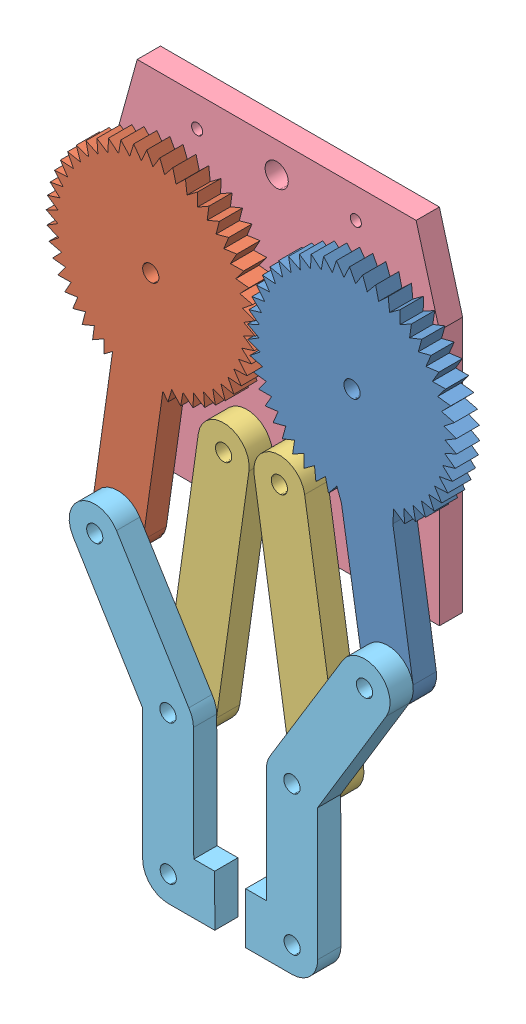
SolidWorks assembly XX, configuration Default. Lengths in mm.
Overall size (106.15 143.99 15).
7 component instances, 5 part files, 14 mates.
Components (placement in the parent):
- p1-1: p1 [Default] at (-416.0921 -344.6097 60.3759) x (0.988737 0.149664 0) z (0 0 1) size (44.91 78 5)
- p1_2-1: p1_2 [Default] at (-541.6496 -222.5672 60.3759) x (0.982822 -0.184555 0) z (0 0 1) size (44.97 77.99 5)
- p2-1: p2 [Default] at (-536.8195 -350.683 60.3759) x (0.990197 -0.139681 0) z (0 0 1) size (11 61 5)
- p2-2: p2 [Default] at (-401.013 -461.8626 60.3759) x (0.988113 0.153729 0) z (0 0 1) size (11 61 5)
- p4-1: p4 [Default] at (-493.5374 -239.3205 55.3759) x (1 0.000279 0) z (0 0 1) size (70 73.03 5)
- p33-2: p33 [Default] at (-38.5492 -79.1672 65.3759) x (0.999998 0.001877 0) z (0 0 1) size (31.17 66.58 5)
- p33-3: p33 [Default] at (-148.7564 -79.4572 70.3759) x (-0.999997 -0.002492 0) z (0 0 -1) size (31.17 66.58 5)
Mates (geometry in assembly coordinates):
- Coincident57: coincident anti-aligned: plane of p1_2-1 through (-541.6496 -222.5672 60.3759) normal (0 0 -1); plane of p4-1 through (-493.5374 -239.3205 60.3759) normal (0 0 1)
- Coincident60: coincident anti-aligned: plane of p2-1 through (-107.0776 -38.4044 60.3759) normal (0 0 -1); plane of p4-1 through (-493.5374 -239.3205 60.3759) normal (0 0 1)
- Coincident61: coincident anti-aligned: plane of p1-1 through (-64.7801 -12.6883 60.3759) normal (0 0 -1); plane of p4-1 through (-493.5374 -239.3205 60.3759) normal (0 0 1)
- Concentric44: concentric aligned: circle of p1-1; circle of p4-1
- Concentric45: concentric aligned: circle of p1_2-1; circle of p4-1
- GearMate1: gear = 3.5 : 3.5 mm: circle of p1_2-1; circle of p1-1
- Concentric66: concentric anti-aligned: cylinder of p1_2-1 through (-122.8162 -12.8644 65.3759) axis (0 0 -1) radius 1.75; cylinder of p33-3 through (-122.8162 -12.8644 65.3759) axis (0 0 1) radius 1.75
- Concentric67: concentric anti-aligned: cylinder of p2-1 through (-107.0776 -38.4044 65.3759) axis (0 0 -1) radius 1.75; cylinder of p33-3 through (-107.0776 -38.4044 65.3759) axis (0 0 1) radius 1.75
- Concentric68: concentric aligned: cylinder of p2-2 through (-80.407 -38.2969 65.3759) axis (0 0 -1) radius 1.75; cylinder of p33-2 through (-80.407 -38.2969 70.3759) axis (0 0 -1) radius 1.75
- Concentric69: concentric aligned: cylinder of p1-1 through (-64.7801 -12.6883 65.3759) axis (0 0 -1) radius 1.75; cylinder of p33-2 through (-64.7801 -12.6883 70.3759) axis (0 0 -1) radius 1.75
- Coincident74: coincident anti-aligned: plane of p2-1 through (-107.0776 -38.4044 65.3759) normal (0 0 1); plane of p33-3 through (-122.8162 -12.8644 65.3759) normal (0 0 -1)
- Coincident75: coincident anti-aligned: plane of p2-2 through (-80.407 -38.2969 65.3759) normal (0 0 1); plane of p33-2 through (-64.7801 -12.6883 65.3759) normal (0 0 -1)
- Concentric70: concentric aligned: cylinder of p2-1 through (-100.0935 11.1054 65.3759) axis (0 0 -1) radius 1.75; cylinder of p4-1 through (-100.0935 11.1054 60.3759) axis (0 0 -1) radius 1.75
- Concentric71: concentric aligned: cylinder of p2-2 through (-88.0935 11.1088 65.3759) axis (0 0 -1) radius 1.75; cylinder of p4-1 through (-88.0935 11.1088 60.3759) axis (0 0 -1) radius 1.75
